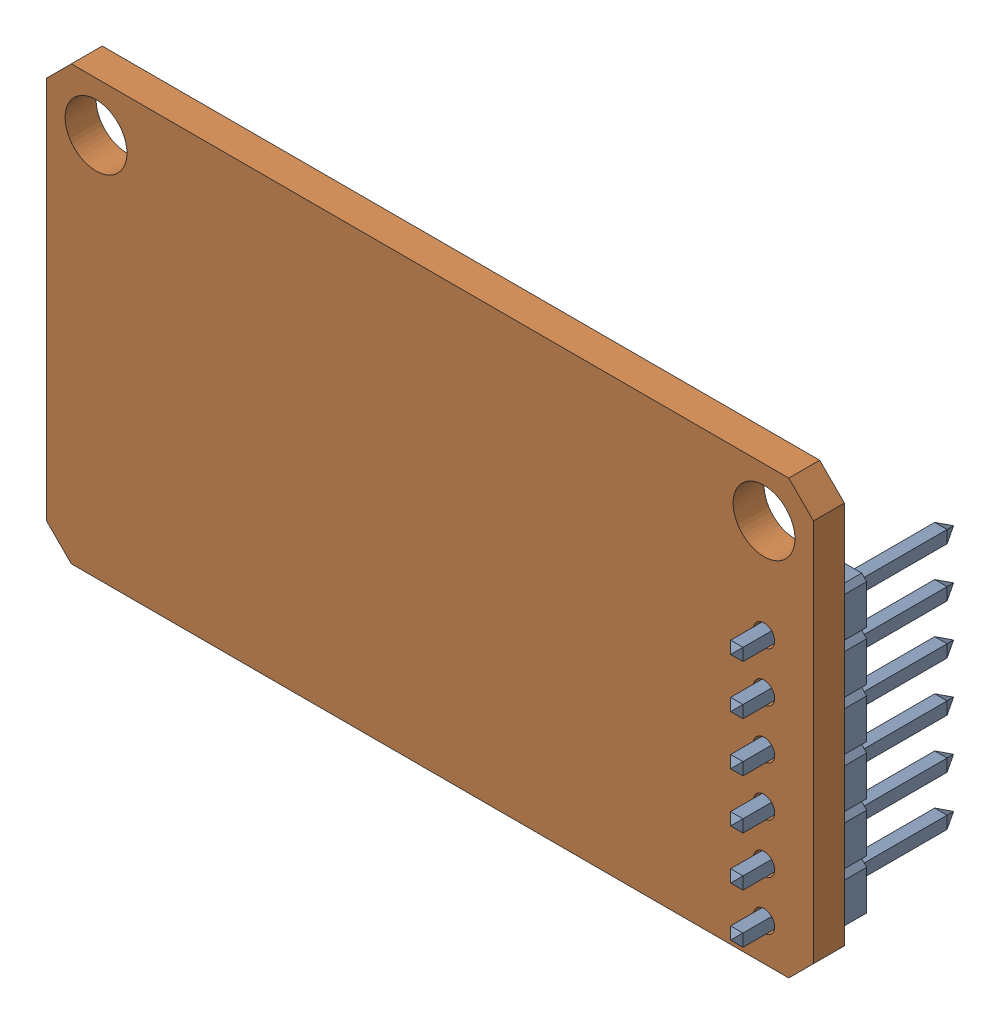
SolidWorks assembly AA5396-1PCB, configuration Default. Lengths in mm.
Overall size (39.37 22.23 11.43).
2 component instances, 2 part files, 0 mates.
Components (placement in the parent):
- CON-0075-1: CON-0075 [Default] at (38.1 15.875 -1.5875) x (0 -1 0) z (0 0 -1) size (15.24 2.54 11.43)
- AA5396PCB-1: AA5396PCB [Default] at origin size (39.37 22.23 1.59)
